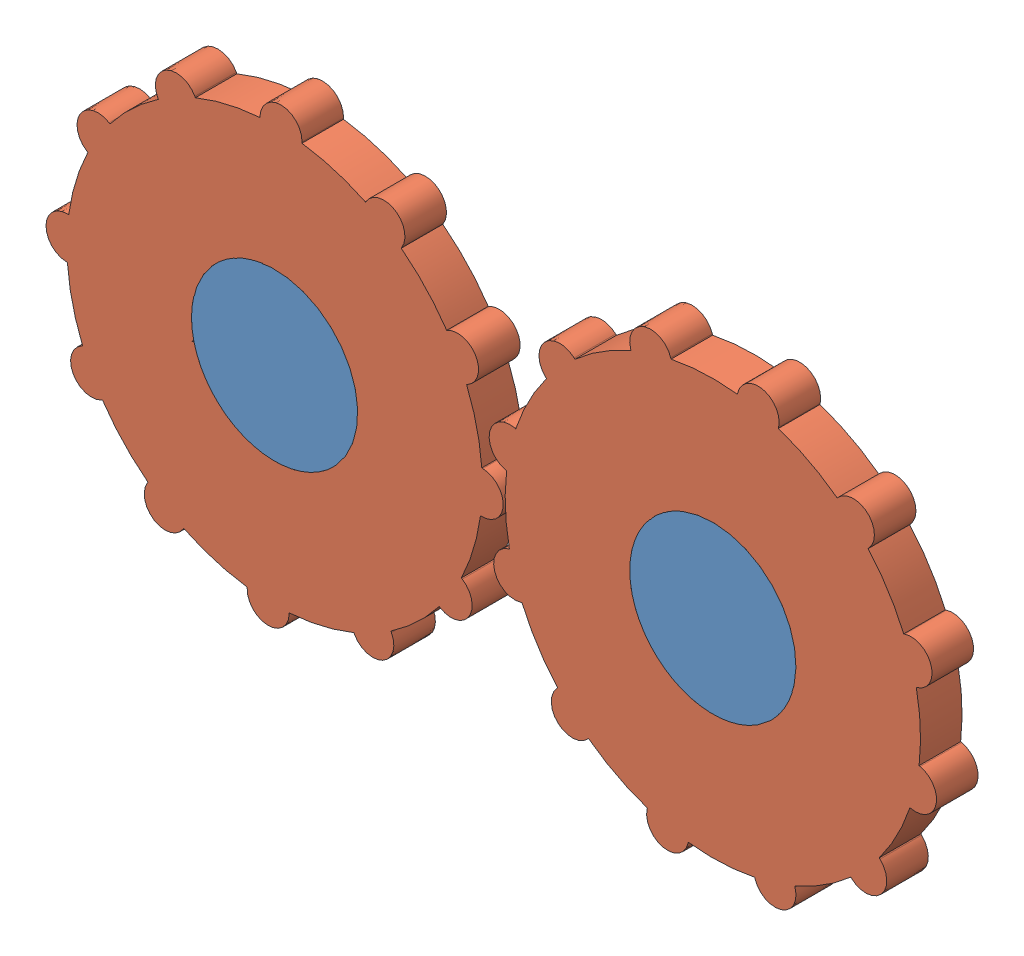
SolidWorks assembly Assem3_anim_2, configuration Default. Lengths in mm.
Overall size (231.23 138.01 10).
3 component instances, 2 part files, 4 mates.
Components (placement in the parent):
- plane_3d_3-1: plane_3d_3 [Default] at (41.2696 82.5704 114.0541) size (145.5 40 10)
- gear_3d-1: gear_3d [Default] at (-10.0994 77.5395 114.0541) x (0.999524 -0.030837 0) z (0 0 1) size (110.11 110.11 10)
- gear_3d-2: gear_3d [Default] at (95.4006 77.5395 114.0541) x (0.954181 0.299231 0) z (0 0 1) size (110.11 110.11 10)
Mates (geometry in assembly coordinates):
- Coincident1: coincident aligned: plane of plane_3d_3-1 through (41.2696 82.5704 124.0541) normal (0 0 1); plane of gear_3d-1 through (-10.0994 77.5395 124.0541) normal (0 0 1)
- Coincident2: coincident aligned: plane of plane_3d_3-1 through (41.2696 82.5704 124.0541) normal (0 0 1); plane of gear_3d-2 through (95.4006 77.5395 124.0541) normal (0 0 1)
- Coincident3: coincident aligned: circle of plane_3d_3-1; circle of gear_3d-1
- Coincident4: coincident aligned: circle of plane_3d_3-1; circle of gear_3d-2
